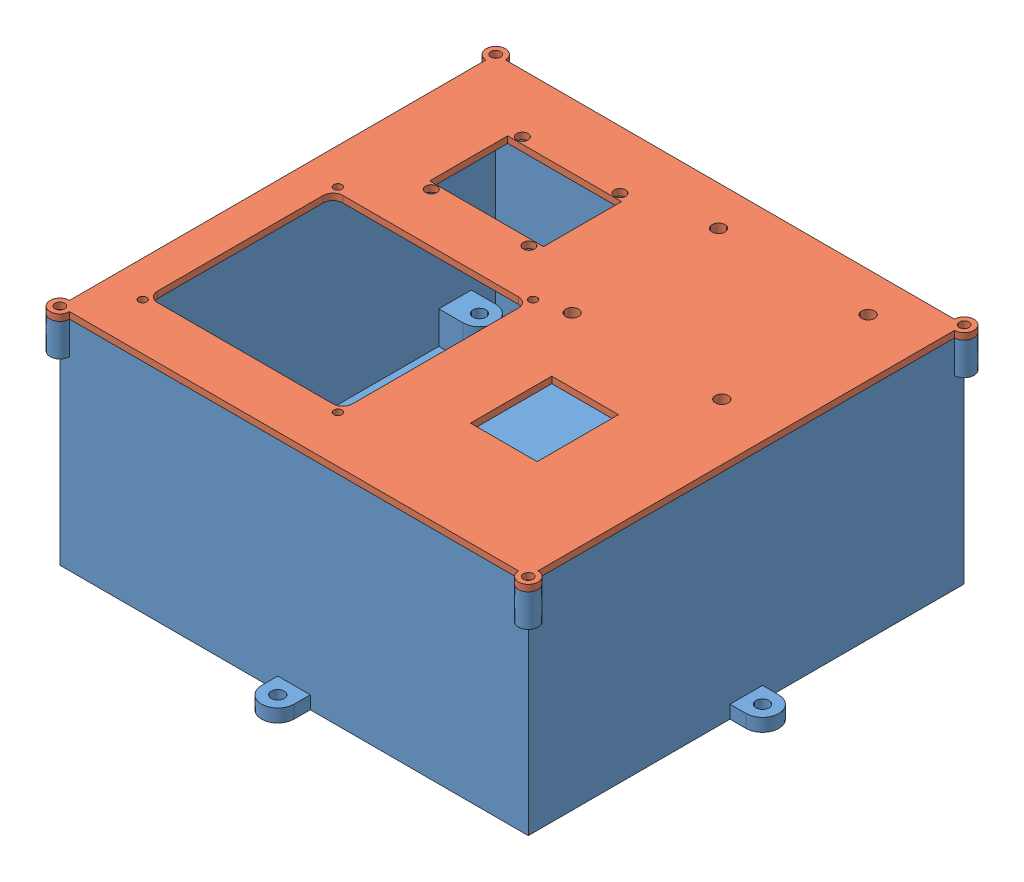
SolidWorks assembly Assem1, configuration Default. Lengths in mm.
Overall size (174.94 74.18 160.18).
2 component instances, 2 part files, 0 mates.
Components (placement in the parent):
- Attendence-1: Attendence [Default] at (47.8009 38.1245 155.8036) size (174.94 74.18 160.18)
- Attendence_top-1: Attendence_top [Default] at (0 103.1245 0) x (1 0 0) z (0 1 0) size (150 140 15)
